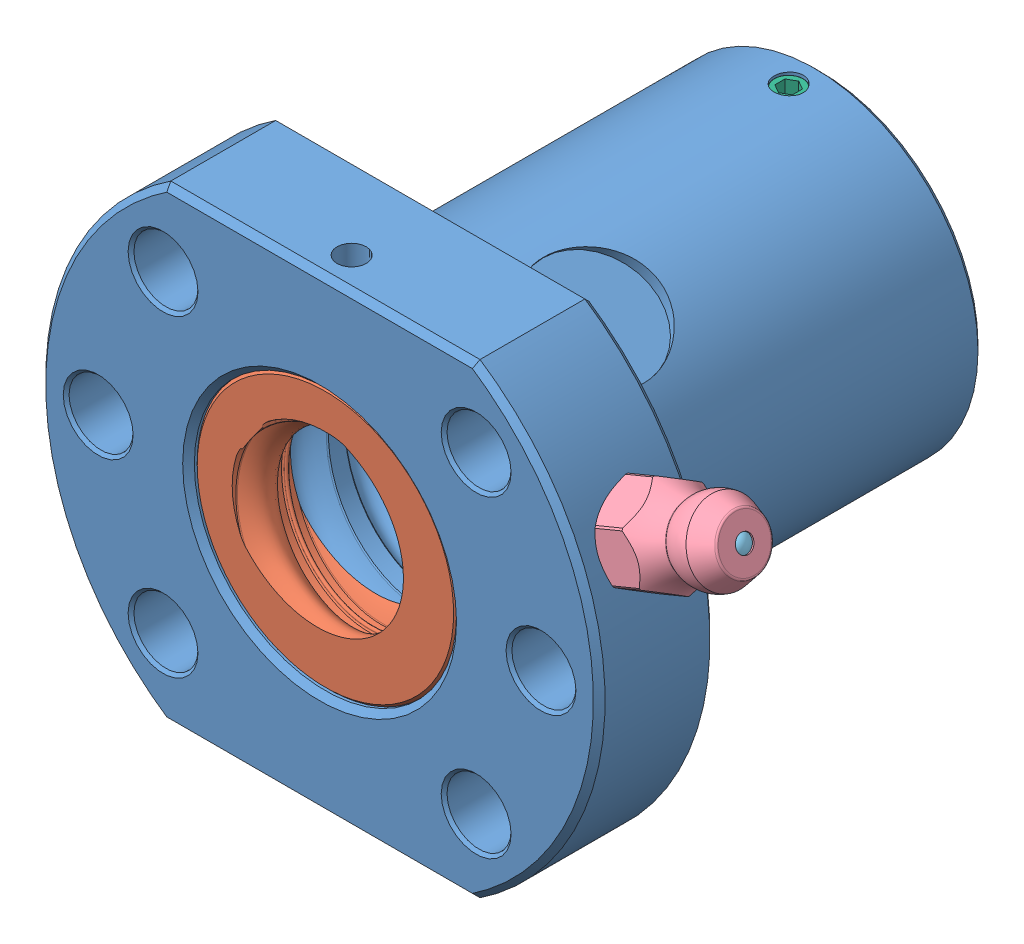
SolidWorks assembly SFU1605-3, configuration Default. Lengths in mm.
Overall size (56.91 40 48.36).
10 component instances, 6 part files, 21 mates.
Components (placement in the parent):
- SFU Ball Nut-1: SFU Ball Nut [1605-3] at origin size (48 40 43)
- SFU1605 Washer Front-1: SFU1605 Washer Front [Default] at origin size (22.5 22.5 11.36)
- SFU1605 Washer Back-1: SFU1605 Washer Back [Default] at origin size (22.5 22.5 11.36)
- Grease Nipple A M6x1.00-2: Grease Nipple A M6x1.00 [Default] at (29.0604 12.0372 -5.25) x (-0.382683 0.92388 0) z (0 0 -1) size (8.34 16.1 7)
  - Grease Nipple A-1: Grease Nipple A [A M6x1.00] at origin size (8.34 16 7)
  - Steel Ball-1: Steel Ball [Ø 2.50] at (0 1.1952 0) size (2.5 2.5 2.5)
- socket set screw cone point_iso-1: socket set screw cone point_iso [ISO 4027 - M3 x 5-C] at (0 16.25 -2.75) x (0 -1 0) z (0 0 -1) size (5 3 3)
- socket set screw cone point_iso-2: socket set screw cone point_iso [ISO 4027 - M3 x 5-C] at (0 -16.25 -2.75) x (0 1 0) z (0 0 1) size (5 3 3)
- socket set screw cone point_iso-3: socket set screw cone point_iso [ISO 4027 - M3 x 2.5-C] at (0 13.75 -40.25) x (0 -1 0) z (0 0 1) size (2.5 3 3)
- socket set screw cone point_iso-4: socket set screw cone point_iso [ISO 4027 - M3 x 2.5-C] at (0 -13.75 -40.25) x (0 1 0) z (0 0 -1) size (2.5 3 3)
Mates (geometry in assembly coordinates):
- Concentric1: concentric aligned: cylinder of SFU Ball Nut-1 through (0 0 0) axis (0 0 1) radius 11.25; cylinder of SFU1605 Washer Front-1 through (0 0 -5.5) axis (0 0 1) radius 11.25
- Coincident1: coincident anti-aligned: plane of SFU Ball Nut-1 through (8.5 0 -5.5) normal (0 0 1); plane of SFU1605 Washer Front-1 through (0 0 -5.5) normal (0 0 -1)
- Parallel1: parallel aligned: plane of SFU Ball Nut-1 through (0 0 0) normal (0 1 0); plane of SFU1605 Washer Front-1 through (0 0 0) normal (0 1 0)
- Concentric2: concentric aligned: cylinder of SFU Ball Nut-1 through (0 0 0) axis (0 0 1) radius 11.25; cylinder of SFU1605 Washer Back-1 through (0 0 -42.5) axis (0 0 1) radius 11.25
- Coincident2: coincident anti-aligned: plane of SFU Ball Nut-1 through (11.25 0 -37.5) normal (0 0 -1); plane of SFU1605 Washer Back-1 through (0 0 -37.5) normal (0 0 1)
- Parallel2: parallel aligned: plane of SFU Ball Nut-1 through (0 0 0) normal (0 1 0); plane of SFU1605 Washer Back-1 through (0 0 0) normal (0 1 0)
- Concentric3: concentric aligned: cylinder of SFU Ball Nut-1 through (0 20 -2.75) axis (0 1 0) radius 1.25; cylinder of socket set screw cone point_iso-1 through (0 28.95 -2.75) axis (0 1 0) radius 1.5
- Concentric4: concentric aligned: cylinder of SFU Ball Nut-1 through (0 20 -40.25) axis (0 1 0) radius 1.25; cylinder of socket set screw cone point_iso-3 through (0 26.45 -40.25) axis (0 1 0) radius 1.5
- Concentric6: concentric anti-aligned: cylinder of SFU Ball Nut-1 through (0 20 -2.75) axis (0 1 0) radius 1.25; cylinder of socket set screw cone point_iso-2 through (0 -28.95 -2.75) axis (0 -1 0) radius 1.5
- Concentric7: concentric anti-aligned: cylinder of SFU Ball Nut-1 through (0 20 -40.25) axis (0 1 0) radius 1.25; cylinder of socket set screw cone point_iso-4 through (0 -26.45 -40.25) axis (0 -1 0) radius 1.5
- Coincident4: coincident: cylinder of SFU1605 Washer Front-1 through (0 0 -5.5) axis (0 0 1) radius 11.25; point of socket set screw cone point_iso-1
- Coincident5: coincident: cylinder of SFU1605 Washer Front-1 through (0 0 -5.5) axis (0 0 1) radius 11.25; point of socket set screw cone point_iso-2
- Coincident6: coincident: cylinder of SFU1605 Washer Back-1 through (0 0 -42.5) axis (0 0 1) radius 11.25; point of socket set screw cone point_iso-4
- Coincident7: coincident: cylinder of SFU1605 Washer Back-1 through (0 0 -42.5) axis (0 0 1) radius 11.25; point of socket set screw cone point_iso-3
- Parallel4: parallel anti-aligned: plane of SFU Ball Nut-1 through (0 0 0) normal (0 0 1); plane of socket set screw cone point_iso-1 through (0 16.25 -2.75) normal (0 0 -1)
- Parallel5: parallel aligned: plane of SFU Ball Nut-1 through (0 0 0) normal (0 0 1); plane of socket set screw cone point_iso-2 through (0 -16.25 -2.75) normal (0 0 1)
- Parallel6: parallel aligned: plane of SFU Ball Nut-1 through (0 0 0) normal (0 0 1); plane of socket set screw cone point_iso-3 through (0 13.75 -40.25) normal (0 0 1)
- Parallel7: parallel anti-aligned: plane of SFU Ball Nut-1 through (0 0 0) normal (0 0 1); plane of socket set screw cone point_iso-4 through (0 -13.75 -40.25) normal (0 0 -1)
- Concentric8: concentric: cylinder of SFU Ball Nut-1 through (22.1731 9.1844 -5.25) axis (0.92388 0.382683 0) radius 2.5; cylinder of Grease Nipple A M6x1.00-2/Grease Nipple A-1 through (5.6191 2.3275 -5.25) axis (-0.92388 -0.382683 0) radius 1.25
- Tangent1: tangent: cylinder of SFU Ball Nut-1 through (0 0 0) axis (0 0 1) radius 24; plane of Grease Nipple A M6x1.00-2/Grease Nipple A-1 through (21.3731 11.1159 -8.6502) normal (-0.92388 -0.382683 0)
- Parallel8: parallel anti-aligned: plane of SFU Ball Nut-1 through (0 0 0) normal (0 0 1); plane of Grease Nipple A M6x1.00-2/Grease Nipple A-1 through (29.0604 12.0372 -5.25) normal (0 0 -1)
